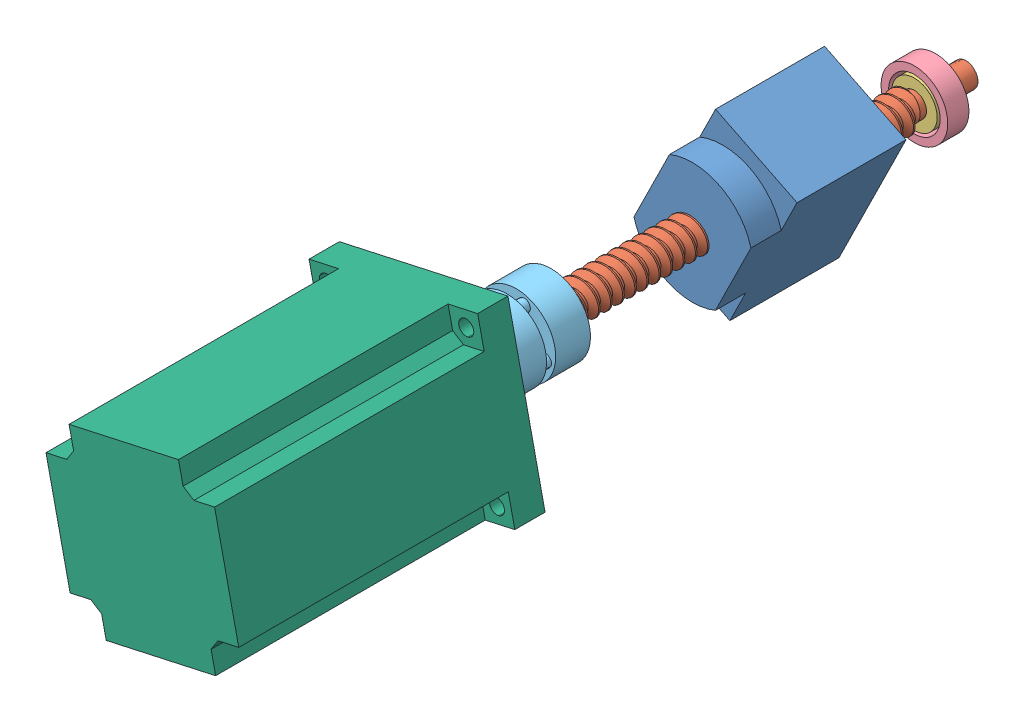
SolidWorks assembly Z drive, configuration Default. Lengths in mm.
Overall size (67.93 67.93 271.9).
9 component instances, 7 part files, 7 mates.
Components (placement in the parent):
- screw block-1: screw block [Default] at (31.8805 56.0141 -158.3925) x (0.443184 0.896431 0) z (0 0 1) size (50 30 47.5)
- Z screw-1: Z screw [Default] at (29.1155 50.6892 -125.9266) x (0 0 1) z (0.887486 -0.460835 0) size (148 12.55 12)
- 608 bearing-1: 608 bearing [Default] at (20.8903 51.6391 -202.4539) x (-0.639932 -0.768431 0) z (0 0 1) size (22 22 7) (flexible)
  - inner race-1: inner race [Default] at (-10.3949 5.6455 9.7773) x (0.715646 0.698463 0) z (0 0 1) size (15 15 7)
  - outer race-1: outer race [Default] at (-10.3949 5.6455 9.7773) size (22 22 7)
- coupling WQ-C26L26-1: coupling WQ-C26L26 [Default] at (31.8805 56.0141 -51.2266) x (-0.26453 -0.964377 0) z (0 0 1) size (26 26 26)
- 57 stepper motor-1: 57 stepper motor [Default] at (92.5617 47.4888 -63.4796) x (-0.215229 0.976564 0) z (0 0 1) size (57 57 120) (flexible)
  - motor body-1: motor body [Default] at (21.3859 57.4242 33.703) size (57 57 100.6)
  - motor axis-1: motor axis [Default] at (21.3859 57.4242 33.703) x (0.450543 0.892755 0) z (0 0 -1) size (8 8 21)
Mates (geometry in assembly coordinates):
- Concentric1: concentric anti-aligned: cylinder of Z screw-1 through (31.8805 56.0141 -54.6766) axis (0 0 1) radius 4; cylinder of 608 bearing-1/inner race-1 through (31.8805 56.0141 -185.6766) axis (0 0 -1) radius 4
- Distance1: distance = 10 mm aligned: plane of Z screw-1 through (29.1155 50.6892 -202.6766) normal (0 0 -1); plane of 608 bearing-1/inner race-1 through (31.8805 56.0141 -192.6766) normal (0 0 -1)
- Concentric2: concentric aligned: cylinder of Z screw-1 through (31.8805 56.0141 -54.6766) axis (0 0 1) radius 4; cylinder of coupling WQ-C26L26-1 through (31.8805 56.0141 -65.7266) axis (0 0 1) radius 4
- Concentric3: concentric anti-aligned: cylinder of coupling WQ-C26L26-1 through (31.8805 56.0141 -39.7266) axis (0 0 -1) radius 4; cylinder of 57 stepper motor-1/motor axis-1 through (31.8805 56.0141 -50.7766) axis (0 0 1) radius 4
- Distance2: distance = 0.45 mm aligned: plane of coupling WQ-C26L26-1 through (31.8805 56.0141 -51.2266) normal (0 0 -1); plane of 57 stepper motor-1/motor axis-1 through (31.8805 56.0141 -50.7766) normal (0 0 -1)
- Distance3: distance = 0.45 mm aligned: plane of Z screw-1 through (29.1155 50.6892 -54.6766) normal (0 0 1); plane of coupling WQ-C26L26-1 through (31.8805 56.0141 -54.2266) normal (0 0 1)
- Screw1: screw = 1 anti-aligned: cylinder of screw block-1 through (31.8805 56.0141 -122.3925) axis (0 0 -1) radius 6; cylinder of Z screw-1 through (31.8805 56.0141 -54.6766) axis (0 0 1) radius 6
